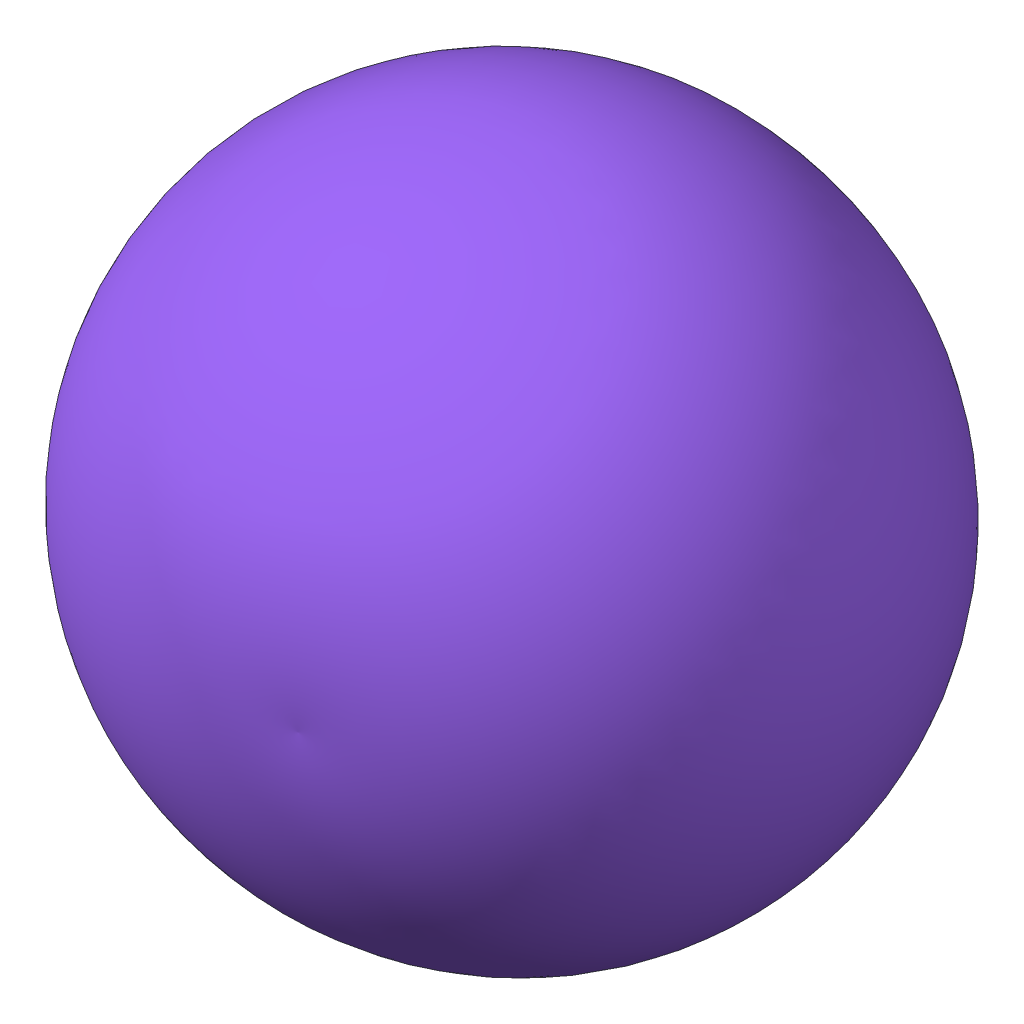
SolidWorks assembly GR6160-3200V1.0 机器人数模, configuration 默认. Lengths in mm.
Overall size (9203.84 7999.44 7506.43).
8 component instances, 8 part files, 18 mates.
Components (placement in the parent):
- 复件 底座^GR6160-3200V1.0 机器人数模-2: 复件 底座^GR6160-3200V1.0 机器人数模 [默认] x (-0.962437 0 0.271506) z (0 1 0) size (600 299 650) (virtual)
- 复件 转座^GR6160-3200V1.0 机器人数模-1: 复件 转座^GR6160-3200V1.0 机器人数模 [默认] x (-0.962435 -0.001954 0.271506) z (-0.001881 0.999998 0.000531) size (595.7 539.7 630.36) (virtual)
- 复件 大臂^GR6160-3200V1.0 机器人数模-1: 复件 大臂^GR6160-3200V1.0 机器人数模 [默认] at (-195.4758 219.2932 640.1179) x (0.001881 -0.999998 -0.000531) z (-0.962435 -0.001954 0.271506) size (453.06 1664 298.53) (virtual)
- 复件 手腕^GR6160-3200V1.0 机器人数模-1: 复件 手腕^GR6160-3200V1.0 机器人数模 [默认] at (573.2328 1688.4968 2044.1487) x (-0.097326 -0.000711 0.995252) z (0.001881 -0.999998 -0.000531) size (149.05 200 223.8) (virtual)
- 复件 小臂^GR6160-3200V1.0 机器人数模-1: 复件 小臂^GR6160-3200V1.0 机器人数模 [默认] at (575.4763 495.4991 2043.5158) x (-0.001881 0.999998 0.000531) z (0.995251 0.00182 0.097328) size (1430.5 162 162) (virtual)
- 复件 法兰^GR6160-3200V1.0 机器人数模-1: 复件 法兰^GR6160-3200V1.0 机器人数模 [默认] at (572.6841 1980.2962 2044.3035) x (-0.001881 0.999998 0.000531) z (0.369144 0.000201 0.929372) size (23.5 102 102) (virtual)
- 复件 电机座^GR6160-3200V1.0 机器人数模-1: 复件 电机座^GR6160-3200V1.0 机器人数模 [默认] at (388.1882 219.7065 1930.1057) x (-0.001881 0.999998 0.000531) z (0.962435 0.001954 -0.271506) size (418 410 432.9) (virtual)
- 复件 运动范围图^GR6160-3200V1.0 机器人数模-1: 复件 运动范围图^GR6160-3200V1.0 机器人数模 [默认] at (-88.1304 0 -312.4049) x (0.926284 -0.271506 -0.261308) z (-0.261308 -0.962437 0.073716) size (6482.83 5542.73 6482.83) (virtual)
Mates (geometry in assembly coordinates):
- 同心2: concentric anti-aligned: circle of 复件 转座^GR6160-3200V1.0 机器人数模-1; circle of 复件 大臂^GR6160-3200V1.0 机器人数模-1
- 距离2: distance = 76.5 mm anti-aligned: plane of 复件 转座^GR6160-3200V1.0 机器人数模-1 through (63.5032 47.0038 538.5133) normal (-0.962435 -0.001954 0.271506); plane of 复件 大臂^GR6160-3200V1.0 机器人数模-1 through (298.5358 3415.5187 1677.6614) normal (0.962435 0.001954 -0.271506)
- 同心13: concentric aligned: circle of 复件 手腕^GR6160-3200V1.0 机器人数模-1; circle of 复件 小臂^GR6160-3200V1.0 机器人数模-1
- 距离9: distance = 12.6 mm anti-aligned: plane of 复件 小臂^GR6160-3200V1.0 机器人数模-1 through (614.7607 1833.5729 2048.3134) normal (0.995251 0.00182 0.097328); plane of 复件 手腕^GR6160-3200V1.0 机器人数模-1 through (627.3009 1833.5959 2049.5397) normal (-0.995251 -0.00182 -0.097328)
- 同心14: concentric aligned: circle of 复件 手腕^GR6160-3200V1.0 机器人数模-1; circle of 复件 法兰^GR6160-3200V1.0 机器人数模-1
- 距离10: distance = 1 mm anti-aligned: plane of 复件 手腕^GR6160-3200V1.0 机器人数模-1 through (567.7252 1977.76 2095.0601) normal (-0.001881 0.999998 0.000531); plane of 复件 法兰^GR6160-3200V1.0 机器人数模-1 through (572.6869 1978.7962 2044.3027) normal (0.001881 -0.999998 -0.000531)
- LimitAngle1: limit planar angle = 0 rad anti-aligned: plane of 复件 转座^GR6160-3200V1.0 机器人数模-1 through (0 0 0) normal (-0.001881 0.999998 0.000531); plane of 复件 大臂^GR6160-3200V1.0 机器人数模-1
- LimitAngle3: limit planar angle = 0 rad aligned: plane of 复件 小臂^GR6160-3200V1.0 机器人数模-1; plane of 复件 手腕^GR6160-3200V1.0 机器人数模-1
- 距离11: distance = 19.5 mm anti-aligned: plane of 复件 转座^GR6160-3200V1.0 机器人数模-1 through (70.3202 0 249.2711) normal (-0.271506 0 -0.962437); plane of 复件 底座^GR6160-3200V1.0 机器人数模-2 through (97.5533 176.7986 221.3275) normal (0.271506 0 0.962437)
- 同心15: concentric anti-aligned: circle of 复件 底座^GR6160-3200V1.0 机器人数模-2; circle of 复件 转座^GR6160-3200V1.0 机器人数模-1
- 同心16: concentric anti-aligned: circle of 复件 大臂^GR6160-3200V1.0 机器人数模-1; circle of 复件 电机座^GR6160-3200V1.0 机器人数模-1
- 距离12: distance = 17.9 mm anti-aligned: plane of 复件 电机座^GR6160-3200V1.0 机器人数模-1 through (408.6261 219.6967 2020.9698) normal (-0.962435 -0.001954 0.271506); plane of 复件 大臂^GR6160-3200V1.0 机器人数模-1 through (366.1484 219.6617 1936.3232) normal (0.962435 0.001954 -0.271506)
- 同心17: concentric aligned: circle of 复件 小臂^GR6160-3200V1.0 机器人数模-1; circle of 复件 电机座^GR6160-3200V1.0 机器人数模-1
- 距离13: distance = 70.5 mm aligned: plane of 复件 小臂^GR6160-3200V1.0 机器人数模-1 through (567.5553 515.4414 2124.1419) normal (-0.001881 0.999998 0.000531); plane of 复件 电机座^GR6160-3200V1.0 机器人数模-1 through (638.4 445.091 2093.0123) normal (-0.001881 0.999998 0.000531)
- LimitAngle4: limit planar angle = 0 rad anti-aligned: plane of 复件 电机座^GR6160-3200V1.0 机器人数模-1; plane of 复件 大臂^GR6160-3200V1.0 机器人数模-1
- 同心18: concentric anti-aligned: circle of 复件 底座^GR6160-3200V1.0 机器人数模-2; circle of 复件 运动范围图^GR6160-3200V1.0 机器人数模-1
- 重合2: coincident: point of 复件 底座^GR6160-3200V1.0 机器人数模-2; point of assembly
- 平行1: parallel anti-aligned: plane of 复件 底座^GR6160-3200V1.0 机器人数模-2 through (-141.6504 -350 50.3503) normal (0 -1 0); plane of assembly through (0 0 0) normal (0 1 0)
